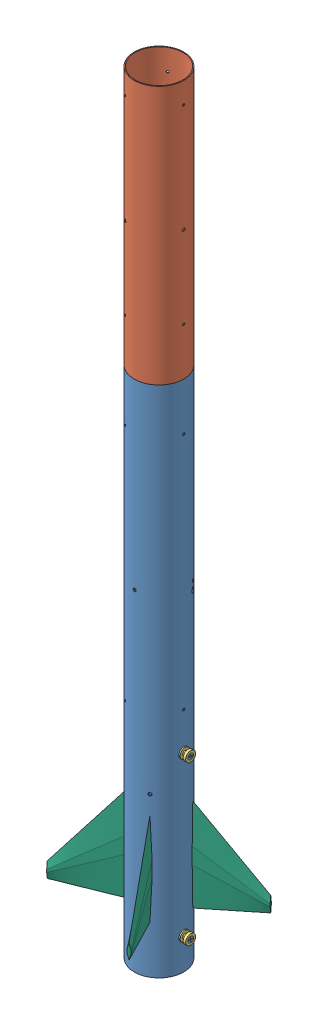
SolidWorks assembly S1B_Airframe, configuration Default. Lengths in mm.
Overall size (229.44 1236.87 229.44).
14 component instances, 6 part files, 18 mates.
Components (placement in the parent):
- S1B_Aft_Body_Tube-2: S1B_Aft_Body_Tube [Default] at origin size (79.25 822.53 79.25)
- S1B_Forward_Body_Tube-1: S1B_Forward_Body_Tube [Default] at (0 822.5282 0) size (79.25 414.34 79.25)
- S1B_Railguide-1: S1B_Railguide [Default] at (39.8526 50.8 0) size (19.05 19 19)
  - S1B_Railguide_Bolt-1: S1B_Railguide_Bolt [Default] at origin size (10.92 16 16)
  - S1B_Welded_Nut_Railguide-1: S1B_Welded_Nut_Railguide [Default] at (-2.6264 0 0) x (0 0 1) z (-1 0 0) size (19 19 11)
  - S1B_10-32_Flathead_RailguideScrew-2: S1B_10-32_Flathead_RailguideScrew [91099A365] at (1.397 0 0) x (-1 0 0) z (0 0 -1) size (19.05 8.95 8.95)
- S1B_Railguide-2: S1B_Railguide [Default] at (39.8526 304.8 0) size (19.05 19 19)
  - S1B_Railguide_Bolt-1: S1B_Railguide_Bolt [Default] at origin size (10.92 16 16)
  - S1B_Welded_Nut_Railguide-1: S1B_Welded_Nut_Railguide [Default] at (-2.6264 0 0) x (0 0 1) z (-1 0 0) size (19 19 11)
  - S1B_10-32_Flathead_RailguideScrew-2: S1B_10-32_Flathead_RailguideScrew [91099A365] at (1.397 0 0) x (-1 0 0) z (0 0 -1) size (19.05 8.95 8.95)
- S1B_Fin_Representation_2-2: S1B_Fin_Representation_2 [Default] at (19.812 150.622 34.3154) x (0.5 0 0.866025) z (-0.866025 0 0.5) size (91.39 148.58 5.04)
- S1B_Fin_Representation_2-3: S1B_Fin_Representation_2 [Default] at (-34.3154 150.622 19.812) x (-0.866025 0 0.5) z (-0.5 0 -0.866025) size (91.39 148.58 5.04)
- S1B_Fin_Representation_2-4: S1B_Fin_Representation_2 [Default] at (-19.812 150.622 -34.3154) x (-0.5 0 -0.866025) z (0.866025 0 -0.5) size (91.39 148.58 5.04)
- S1B_Fin_Representation_2-5: S1B_Fin_Representation_2 [Default] at (34.3154 150.622 -19.812) x (0.866025 0 -0.5) z (0.5 0 0.866025) size (91.39 148.58 5.04)
Mates (geometry in assembly coordinates):
- Coincident1: coincident anti-aligned: line of S1B_Aft_Body_Tube-2 through (894.08 0 -40.64) axis (0 0 1)
- Coincident2: coincident aligned: plane of S1B_Aft_Body_Tube-2 through (0 0 0) normal (0 1 0)
- Parallel1: parallel aligned: plane of S1B_Aft_Body_Tube-2 through (0 0 0) normal (0 0 1)
- Coincident3: coincident anti-aligned: line of S1B_Forward_Body_Tube-1 through (167.64 0 814.9082) axis (0 0 1)
- Coincident4: coincident aligned: plane of S1B_Aft_Body_Tube-2 through (0 822.5282 0) normal (0 1 0); plane of S1B_Forward_Body_Tube-1 through (0 822.5282 0) normal (0 1 0)
- Parallel2: parallel aligned: plane of S1B_Forward_Body_Tube-1 through (0 822.5282 0) normal (0 0 1)
- Concentric1: concentric anti-aligned: cylinder of S1B_Aft_Body_Tube-2 through (-39.625 304.8 0) axis (1 0 0) radius 3.175; cylinder of S1B_Railguide-2/S1B_Welded_Nut_Railguide-1 through (48.227 304.8 0) axis (-1 0 0) radius 3.1979
- Tangent2: tangent aligned: cylinder of S1B_Aft_Body_Tube-2 through (0 822.5282 0) axis (0 -1 0) radius 38.227; plane of S1B_Railguide-2/S1B_Welded_Nut_Railguide-1 through (38.227 304.8 0) normal (1 0 0)
- Coincident5: coincident aligned: plane of S1B_Railguide-1/S1B_Welded_Nut_Railguide-1 through (38.227 50.8 0) normal (1 0 0); plane of S1B_Railguide-2/S1B_Welded_Nut_Railguide-1 through (38.227 304.8 0) normal (1 0 0)
- Concentric2: concentric anti-aligned: cylinder of S1B_Aft_Body_Tube-2 through (-39.625 50.8 0) axis (1 0 0) radius 3.175; cylinder of S1B_Railguide-1/S1B_Welded_Nut_Railguide-1 through (48.227 50.8 0) axis (-1 0 0) radius 3.1979
- Parallel3: parallel aligned: plane of S1B_Railguide-1 through (39.8526 50.8 0) normal (0 1 0)
- Parallel4: parallel aligned: plane of S1B_Railguide-2 through (39.8526 304.8 0) normal (0 1 0)
- Coincident10: coincident aligned: plane of S1B_Fin_Representation-8 through (28.0184 228.6 28.0184) normal (0.707107 0 -0.707107)
- Coincident11: coincident aligned: plane of S1B_Fin_Representation-8 through (28.0184 228.6 28.0184) normal (0.707107 0 0.707107)
- Distance4: distance = 228.6 mm aligned: plane of S1B_Fin_Representation-8 through (28.0184 228.6 28.0184) normal (0 -1 0); plane of S1B_Aft_Body_Tube-2 through (0 0 0) normal (0 -1 0)
- Coincident12: coincident aligned: plane of S1B_Aft_Body_Tube-2 through (19.812 0 34.3154) normal (0.5 0 0.866025); plane of S1B_Fin_Representation_2-2 through (19.812 150.622 34.3154) normal (0.5 0 0.866025)
- Coincident13: coincident anti-aligned: plane of S1B_Aft_Body_Tube-2 through (0 0 0) normal (0.866025 0 -0.5); plane of S1B_Fin_Representation_2-2 through (19.812 150.622 34.3154) normal (-0.866025 0 0.5)
- Distance5: distance = 76.2 mm aligned: plane of S1B_Fin_Representation_2-2 through (19.812 76.2 34.3154) normal (0 1 0)
